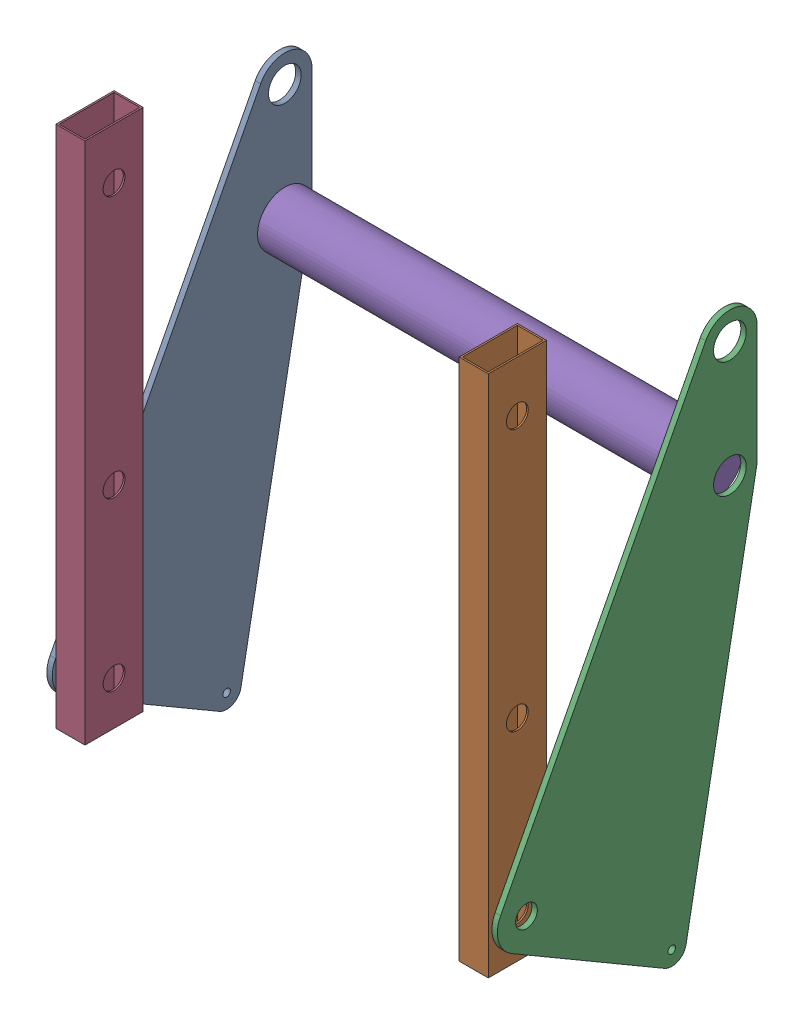
SolidWorks assembly intake_3_1, configuration Default. Lengths in mm.
Overall size (393.82 520.7 236.69).
5 component instances, 3 part files, 0 mates.
Components (placement in the parent):
- intake_side_rev3SLDPRT.2-1: intake_side_rev3SLDPRT.2 [Default] at (-293.803 45.2132 287.1603) size (4.76 471.49 227.01)
- end_link_Default_As Machined_.6-1: end_link_Default_As Machined_.6 [Default] at (79.2595 108.7132 261.7603) size (25.4 457.2 50.8)
- intake_side_rev3SLDPRT.2-2: intake_side_rev3SLDPRT.2 [Default] at (95.1345 45.2132 287.1603) size (4.76 471.49 227.01)
- end_link_Default_As Machined_.6-2: end_link_Default_As Machined_.6 [Default] at (-273.1655 108.7132 261.7603) size (25.4 457.2 50.8)
- intake_roller.4-1: intake_roller.4 [Default] at (-293.9207 391.2882 83.9603) x (1 0 0) z (0 0.77759 0.628772) size (381 47.62 47.62)
